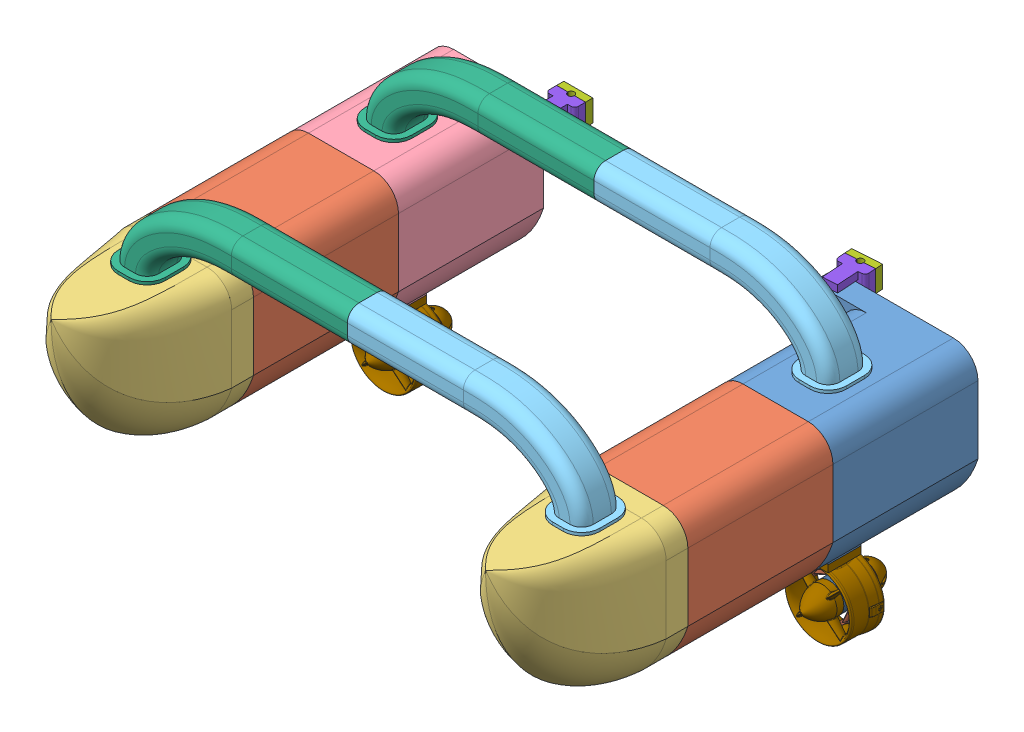
SolidWorks assembly Assemblageboatvirsion2+motors, configuration Défaut. Lengths in mm.
Overall size (767.24 423.37 636.92).
28 component instances, 11 part files, 19 mates.
Components (placement in the parent):
- Assemblagehull1-1: Assemblagehull1 [Défaut] at (-9.9267 302.1646 611.8727) size (203.18 223.75 607.68)
  - body_back_2-1: body_back_2 [Défaut] at (59.9179 -48.2398 110) size (198 212 220)
  - body_mid-1: body_mid [Défaut] at (59.9179 -48.2398 310) size (158 208.49 220)
  - body_front-1: body_front [Défaut] at (59.9179 -48.2398 510) size (168.2 223.75 207.68)
- Assemblagehull2-1: Assemblagehull2 [Défaut] at (-540.1584 218.1203 669.6338) size (203.03 223.75 607.68)
  - body_back2-1: body_back2 [Défaut] at (-8.8859 35.8046 52.2389) size (198 212 220)
  - body_mid-1: body_mid [Défaut] at (-8.8859 35.8046 252.2389) size (158 208.49 220)
  - body_front-1: body_front [Défaut] at (-8.8859 35.8046 452.2389) size (168.2 223.75 207.68)
- Assemblage_support-1: Assemblage_support [Défaut] at (-546.9504 403.2709 986.6766) x (0 0 -1) z (1 0 0) size (75 117.02 664.04)
  - support_numero2-1: support_numero2 [Défaut] at (141.9181 50.18 169.7744) size (75 117.02 352.02)
  - support_numero1-1: support_numero1 [Défaut] at (142.6897 50.18 169.7744) x (-1 0 0) z (0 0 -1) size (75 117.02 332.02)
- Assemblage_support-2: Assemblage_support [Défaut] at (-546.9504 403.2709 1326.6766) x (0 0 -1) z (1 0 0) size (75 117.02 664.04)
  - support_numero2-1: support_numero2 [Défaut] at (141.9181 50.18 169.7744) size (75 117.02 352.02)
  - support_numero1-1: support_numero1 [Défaut] at (142.6897 50.18 169.7744) x (-1 0 0) z (0 0 -1) size (75 117.02 332.02)
- Assemblage support fillet-1: Assemblage support fillet [Défaut] at (-164.556 309.4509 703.6012) x (0.997755 0 -0.066975) z (0 1 0) size (40 55 50)
  - support_fillet2_virsion2-1: support_fillet2_virsion2 [Défaut] at (-4.3035 15.6137 40) size (40 10 30)
  - support_fillet1_virsion2-1: support_fillet1_virsion2 [Défaut] at (-4.3035 -14.3863 70) x (1 0 0) z (0 0 -1) size (40 45 50)
- Assemblage support fillet-2: Assemblage support fillet [Défaut] at (-563.3903 309.4509 704.4864) x (1 0 0) z (0 1 0) size (40 55 50)
  - support_fillet2_virsion2-1: support_fillet2_virsion2 [Défaut] at (-4.3035 15.6137 40) size (40 10 30)
  - support_fillet1_virsion2-1: support_fillet1_virsion2 [Défaut] at (-4.3035 -14.3863 70) x (1 0 0) z (0 0 -1) size (40 45 50)
- corp motor avec axe-1: corp motor avec axe [Défaut] at (-757.2179 148.4005 892.1612) x (1 0 0) z (0 0 -1) size (96.71 104.35 112.68)
  - corps motor version 2-2: corps motor version 2 [Default] at (81.7965 46.9497 49.4946) size (96.71 104.35 112.68)
  - fans-3: fans [Default] at (81.7965 46.9497 47.9921) x (0.002537 0.999997 0) z (0 0 1) size (73.11 65.39 30.02)
  - axe corps motor-2: axe corps motor [Default] at (81.7965 46.9497 49.4946) x (0.999998 -0.001745 0) z (0 0 1) size (87.46 87.46 52.04)
- corp motor avec axe-2: corp motor avec axe [Défaut] at (-158.1824 148.4005 892.1612) x (1 0 0) z (0 0 -1) size (96.71 104.35 112.68)
  - corps motor version 2-2: corps motor version 2 [Default] at (81.7965 46.9497 49.4946) size (96.71 104.35 112.68)
  - fans-3: fans [Default] at (81.7965 46.9497 47.9921) x (0.002537 0.999997 0) z (0 0 1) size (73.11 65.39 30.02)
  - axe corps motor-2: axe corps motor [Default] at (81.7965 46.9497 49.4946) x (0.999998 -0.001745 0) z (0 0 1) size (87.46 87.46 52.04)
Mates (geometry in assembly coordinates):
- Coïncidente3: coincident anti-aligned: plane of Assemblagehull1-1/body_back_2-1 through (-32.6583 369.4509 921.8727) normal (0 1 0); plane of Assemblage_support-1/support_numero2-1 through (-70.1583 369.4509 831.8727) normal (0 -1 0)
- Coaxiale1: concentric anti-aligned: cylinder of Assemblagehull1-1/body_back_2-1 through (-70.1583 359.4509 856.8727) axis (0 1 0) radius 10; cylinder of Assemblage_support-1/support_numero2-1 through (-70.1583 374.4509 856.8727) axis (0 -1 0) radius 10
- Coaxiale2: concentric anti-aligned: cylinder of Assemblagehull1-1/body_back_2-1 through (-85.1583 359.4509 856.8727) axis (0 1 0) radius 10; cylinder of Assemblage_support-1/support_numero2-1 through (-85.1583 374.4509 856.8727) axis (0 -1 0) radius 10
- Coaxiale3: concentric anti-aligned: cylinder of Assemblagehull2-1/body_back2-1 through (-669.1938 359.4509 856.8727) axis (0 1 0) radius 10; cylinder of Assemblage_support-1/support_numero1-1 through (-669.1938 374.4509 856.8727) axis (0 -1 0) radius 12
- Coaxiale4: concentric anti-aligned: cylinder of Assemblagehull2-1/body_back2-1 through (-684.1938 359.4509 856.8727) axis (0 1 0) radius 10; cylinder of Assemblage_support-1/support_numero1-1 through (-684.1938 374.4509 856.8727) axis (0 -1 0) radius 12
- Coïncidente4: coincident anti-aligned: plane of Assemblagehull2-1/body_back2-1 through (-631.6938 369.4509 921.8727) normal (0 1 0); plane of Assemblage_support-1/support_numero1-1 through (-684.1938 369.4509 856.8727) normal (0 -1 0)
- Coaxiale5: concentric anti-aligned: cylinder of Assemblagehull2-1/body_front-1 through (-669.1938 359.4509 1196.8727) axis (0 1 0) radius 10; cylinder of Assemblage_support-2/support_numero1-1 through (-669.1938 374.4509 1196.8727) axis (0 -1 0) radius 12
- Coaxiale6: concentric anti-aligned: cylinder of Assemblagehull2-1/body_front-1 through (-684.1938 359.4509 1196.8727) axis (0 1 0) radius 10; cylinder of Assemblage_support-2/support_numero1-1 through (-684.1938 374.4509 1196.8727) axis (0 -1 0) radius 12
- Coïncidente5: coincident anti-aligned: plane of Assemblagehull2-1/body_front-1 through (-721.6938 369.4509 1151.8727) normal (0 1 0); plane of Assemblage_support-2/support_numero1-1 through (-684.1938 369.4509 1196.8727) normal (0 -1 0)
- Coaxiale7: concentric aligned: cylinder of Assemblagehull1-1/body_back_2-1 through (-176.6583 324.4509 736.8727) axis (0 1 0) radius 6; cylinder of Assemblage support fillet-1/support_fillet1_virsion2-1 through (-176.6583 329.4509 736.8727) axis (0 1 0) radius 6
- Coïncidente6: coincident anti-aligned: plane of Assemblagehull1-1/body_back_2-1 through (-32.6583 369.4509 921.8727) normal (0 1 0); plane of Assemblage support fillet-1/support_fillet1_virsion2-1 through (-167.8863 369.4509 718.2434) normal (0 -1 0)
- Coaxiale8: concentric aligned: cylinder of Assemblagehull2-1/body_back2-1 through (-577.6938 304.4509 736.8727) axis (0 1 0) radius 6; cylinder of Assemblage support fillet-2/support_fillet1_virsion2-1 through (-577.6938 329.4509 736.8727) axis (0 1 0) radius 6
- Coïncidente7: coincident anti-aligned: plane of Assemblagehull2-1/body_back2-1 through (-631.6938 369.4509 921.8727) normal (0 1 0); plane of Assemblage support fillet-2/support_fillet1_virsion2-1 through (-567.6938 369.4509 718.8727) normal (0 -1 0)
- Coïncidente8: coincident anti-aligned: plane of Assemblagehull1-1/body_back_2-1 through (49.9912 157.4509 721.8727) normal (0 -1 0); plane of corp motor avec axe-2/corps motor version 2-2 through (-76.3859 157.4509 842.6667) normal (0 1 0)
- Coïncidente9: coincident aligned: plane of Assemblagehull1-1/body_back_2-1 through (49.9912 187.4509 821.8727) normal (0 0 -1); plane of corp motor avec axe-2/corps motor version 2-2 through (-76.3859 157.4509 821.8727) normal (0 0 -1)
- Coïncidente10: coincident aligned: plane of Assemblagehull1-1/body_back_2-1 through (-60.1583 187.4509 721.8727) normal (1 0 0); plane of corp motor avec axe-2/corps motor version 2-2 through (-60.1583 157.4509 842.6667) normal (1 0 0)
- Coïncidente11: coincident anti-aligned: plane of Assemblagehull2-1/body_back2-1 through (-549.0443 157.4509 721.8727) normal (0 -1 0); plane of corp motor avec axe-1/corps motor version 2-2 through (-675.4213 157.4509 842.6667) normal (0 1 0)
- Coïncidente12: coincident aligned: plane of Assemblagehull2-1/body_back2-1 through (-549.0443 187.4509 821.8727) normal (0 0 -1); plane of corp motor avec axe-1/corps motor version 2-2 through (-675.4213 157.4509 821.8727) normal (0 0 -1)
- Coïncidente13: coincident aligned: plane of Assemblagehull2-1/body_back2-1 through (-659.1938 187.4509 721.8727) normal (1 0 0); plane of corp motor avec axe-1/corps motor version 2-2 through (-659.1938 157.4509 842.6667) normal (1 0 0)
